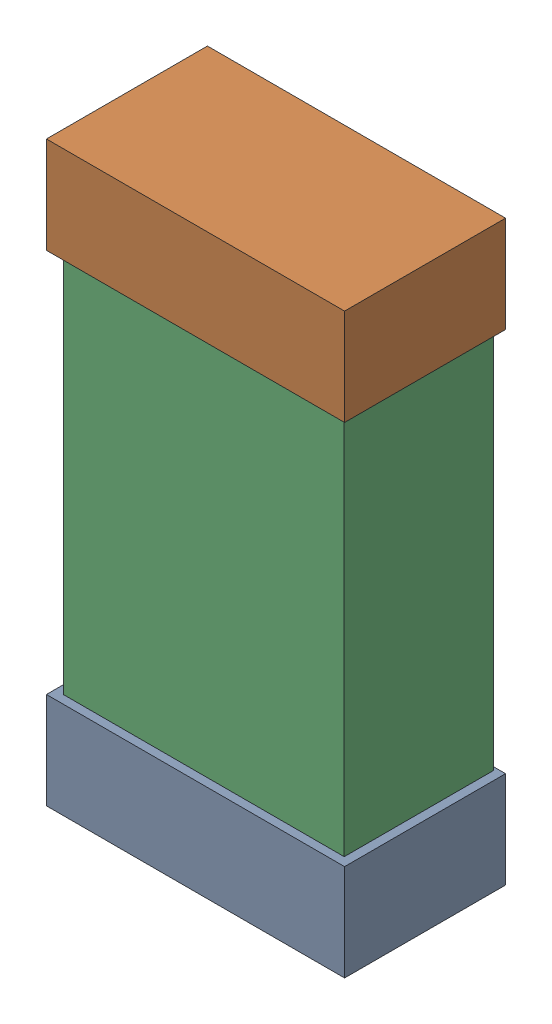
SolidWorks assembly C46, configuration Default. Lengths in mm.
Overall size (0.85 1.65 0.46).
6 component instances, 2 part files, 0 mates.
Components (placement in the parent):
- 432138512_32-1: 432138512_32 [Default] at (36.6333 40.3143 -0.8715) size (0.85 0.28 0.46)
  - Extruded-1: Extruded [Default] at origin size (0.85 0.28 0.46)
- 432138512_33-1: 432138512_33 [Default] at (36.6333 41.6858 -0.8715) size (0.85 0.28 0.46)
  - Extruded-1: Extruded [Default] at origin size (0.85 0.28 0.46)
- 432124816_16-1: 432124816_16 [Default] at (36.6333 41 -0.8615) size (0.8 1.5 0.42)
  - Extruded (1)-1: Extruded (1) [Default] at origin size (0.8 1.5 0.42)
